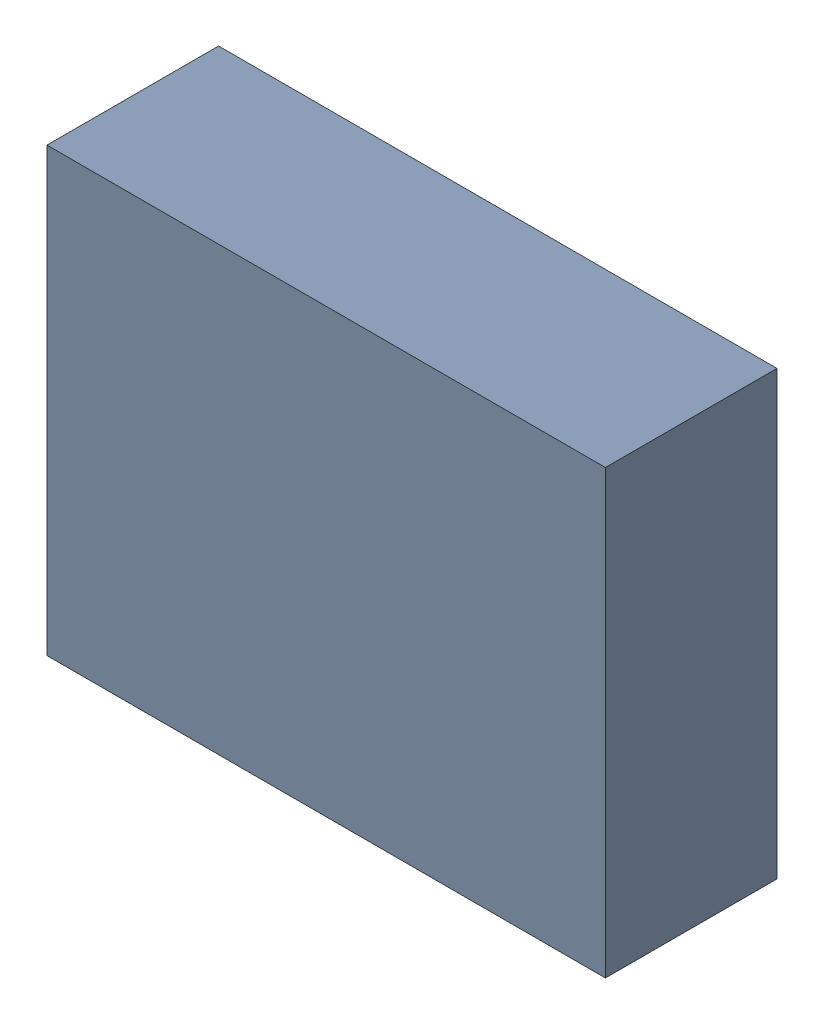
SolidWorks assembly OP2_1, configuration Default. Lengths in mm.
Overall size (5.04 3.99 1.55).
2 component instances, 1 part files, 0 mates.
Components (placement in the parent):
- 407985952_1-1: 407985952_1 [Default] at (34.798 10.287 0.2157) size (5.04 3.99 1.55)
  - Extruded_11-1: Extruded_11 [Default] at origin size (5.04 3.99 1.55)
